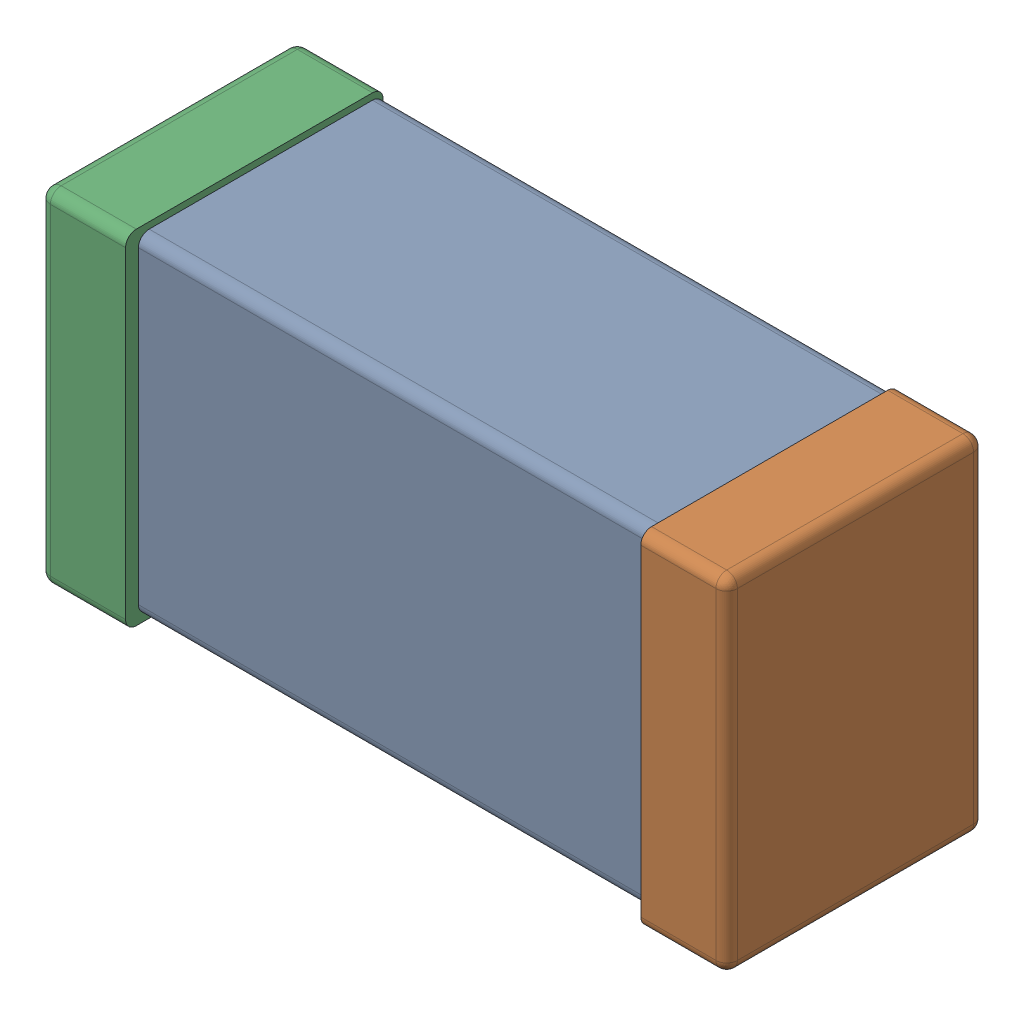
SolidWorks assembly C0603_060_1, configuration Standard. Lengths in mm.
Overall size (1.6 0.8 0.6).
3 component instances, 3 part files, 0 mates.
Components (placement in the parent):
- Part 3_1-1: Part 3_1 [Standard] at (0 0 -23.815) size (1.4 0.77 0.57)
- Part 2_1-1: Part 2_1 [Standard] at (0 0 -23.8) size (0.2 0.8 0.6)
- Part 1_1-1: Part 1_1 [Standard] at (0 0 -23.8) size (0.2 0.8 0.6)
